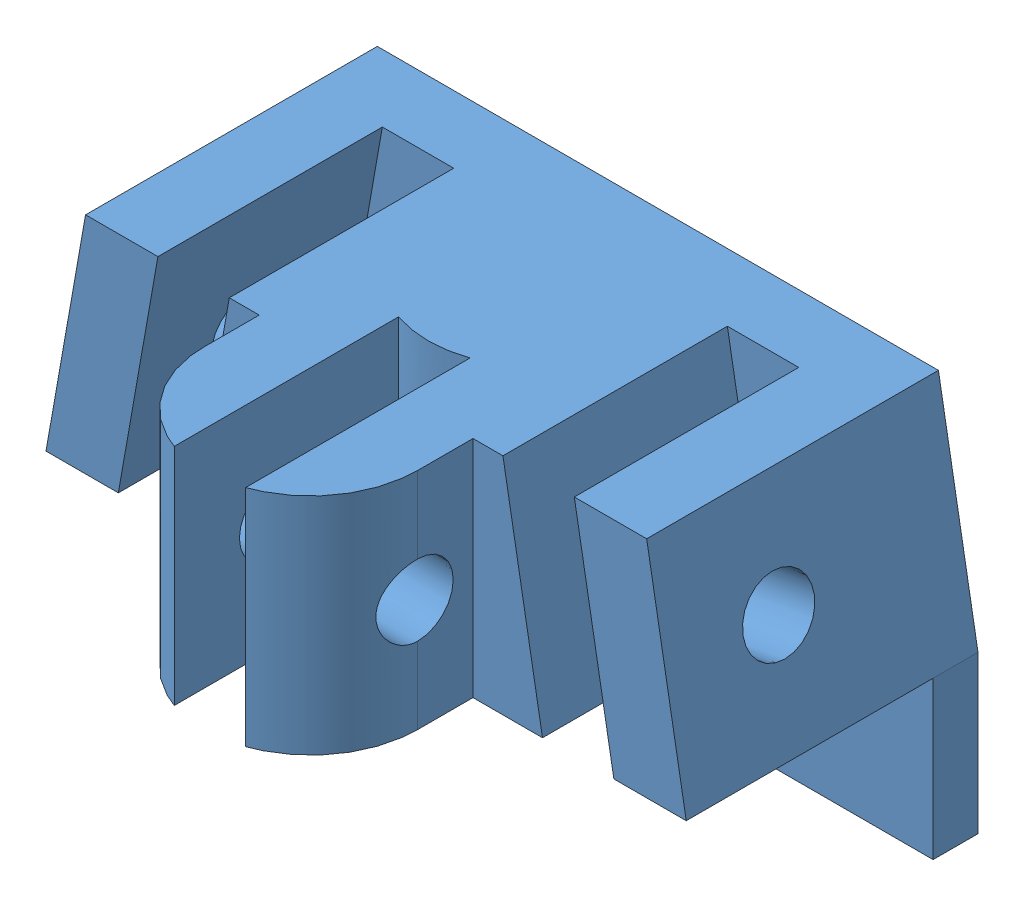
SolidWorks assembly pulley_assem, configuration Default. Lengths in mm.
Overall size (28.53 17.01 19.97).
4 component instances, 2 part files, 4 mates.
Components (placement in the parent):
- Pulley_general-1: Pulley_general [Default] at (7.3534 6.1594 14.9654) size (28.53 17.01 19.97)
- Pulley-1: Pulley [3434T31] at (21.6192 11.1594 30.4338) x (0 0.954062 0.29961) z (1 0 0) (suppressed, hidden)
- Pulley-2: Pulley [3434T31] at (30.3082 10.3324 22.9654) x (0.016778 -0.095151 -0.995321) z (0.984808 0.173648 0) (suppressed, hidden)
- Pulley-3: Pulley [3434T31] at (12.8825 10.34 22.9654) x (-0.019111 -0.108385 0.993925) z (-0.984808 0.173648 0) (suppressed, hidden)
Mates (geometry in assembly coordinates):
- Coincident1: coincident: circle of Pulley_general-1; circle of Pulley-1
- Concentric1: concentric aligned: cylinder of Pulley_general-1 through (12.3641 11.1594 30.4338) axis (1 0 0) radius 1.5875; cylinder of Pulley-1 through (23.2067 11.1594 30.4338) axis (1 0 0) radius 1.5875
- Coincident2: coincident aligned: circle of Pulley_general-1; circle of Pulley-3
- Coincident3: coincident aligned: circle of Pulley_general-1; circle of Pulley-2
